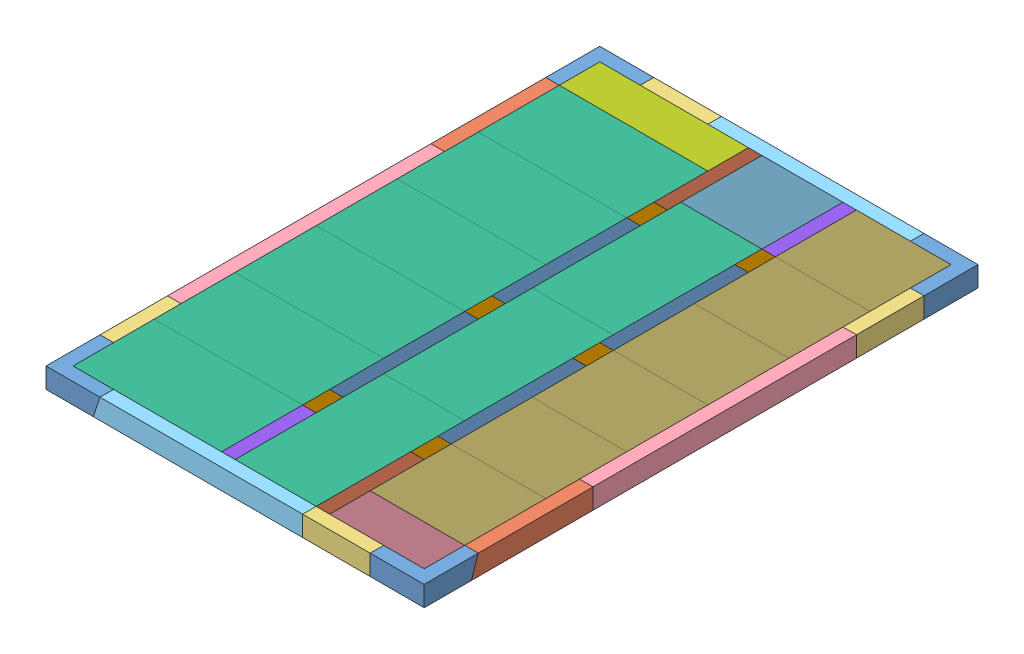
SolidWorks assembly test, configuration 默认. Lengths in mm.
Overall size (2800 228 4100).
46 component instances, 14 part files, 0 mates.
Components (placement in the parent):
- 10x15Z40A+40-5: 10x15Z40A+40 [默认] at (80031.9977 2785.0001 -12041.9998) x (0 0 1) z (0 1 0) size (400 400 150)
- 10x15J85RB-1: 10x15J85RB [默认] at (80031.9977 2785.0001 -10791.9998) x (-1 0 0) z (0 0 -1) size (100 150 900)
- 10x15J50-1: 10x15J50 [默认] at (80031.9977 2785.0001 -8342) x (-1 0 0) z (0 0 -1) size (100 150 500)
- 10x15J195-3: 10x15J195 [默认] at (80031.9977 2785.0001 -8842) x (-1 0 0) z (0 0 -1) size (100 150 1950)
- 10x15Z40A+40-6: 10x15Z40A+40 [默认] at (82832.0007 2785.0001 -12041.9998) x (-1 0 0) z (0 1 0) size (400 400 150)
- 10x15J150RB-3: 10x15J150RB [默认] at (80931.9992 2785.0001 -12041.9998) x (0 0 -1) z (1 0 0) size (100 150 1550)
- 10x15J50-2: 10x15J50 [默认] at (80431.9992 2785.0001 -12041.9998) x (0 0 -1) z (1 0 0) size (100 150 500)
- 10x15Z40A+40-8: 10x15Z40A+40 [默认] at (82832.0007 2785.0001 -7941.9999) x (0 0 -1) z (0 1 0) size (400 400 150)
- 10x15J85RB-2: 10x15J85RB [默认] at (82832.0007 2785.0001 -9192.0004) size (100 150 900)
- 10x15J50-5: 10x15J50 [默认] at (82832.0007 2785.0001 -11642.0002) size (100 150 500)
- 10x15J195-2: 10x15J195 [默认] at (82832.0007 2785.0001 -11142.0002) size (100 150 1950)
- 10x15Z40A+40-7: 10x15Z40A+40 [默认] at (80031.9977 2785.0001 -7941.9999) x (1 0 0) z (0 1 0) size (400 400 150)
- 10x15J150RB-2: 10x15J150RB [默认] at (81931.9992 2785.0001 -7941.9999) x (0 0 1) z (-1 0 0) size (100 150 1550)
- 10x15J50-6: 10x15J50 [默认] at (82431.9992 2785.0001 -7941.9999) x (0 0 1) z (-1 0 0) size (100 150 500)
- 60D110-1: 60D110 [默认] at (80132.0038 2785.0001 -8041.9998) x (0 0 -1) z (-1 0 0) size (600 65 1100)
- 60D110-2: 60D110 [默认] at (80132.0038 2785.0001 -8642.0002) x (0 0 -1) z (-1 0 0) size (600 65 1100)
- 60D110-3: 60D110 [默认] at (80132.0038 2785.0001 -9241.9996) x (0 0 -1) z (-1 0 0) size (600 65 1100)
- 60D110-4: 60D110 [默认] at (80132.0038 2785.0001 -9842) x (0 0 -1) z (-1 0 0) size (600 65 1100)
- 60D110-5: 60D110 [默认] at (80132.0038 2785.0001 -10442.0004) x (0 0 -1) z (-1 0 0) size (600 65 1100)
- 60D110-6: 60D110 [默认] at (80132.0038 2785.0001 -11041.9998) x (0 0 -1) z (-1 0 0) size (600 65 1100)
- 30D110-1: 30D110 [默认] at (80132.0038 2785.0001 -11642.0002) x (0 0 -1) z (-1 0 0) size (300 65 1100)
- DG60-1: DG60 [默认] at (81232.0023 2785.0001 -8041.9998) x (1 0 0) z (0 1 0) size (130 625.48 70)
- LXC-1: LXC [默认] at (81232.0023 2785.0001 -8842) x (0 0 1) z (0 1 0) size (200 100 228)
- ZG100-1: ZG100 [默认] at (81232.0023 2785.0001 -8842) x (1 0 0) z (0 1 0) size (130 1050.96 70)
- LXC-2: LXC [默认] at (81232.0023 2785.0001 -10041.9998) x (0 0 1) z (0 1 0) size (200 100 228)
- ZG100-2: ZG100 [默认] at (81232.0023 2785.0001 -10041.9998) x (1 0 0) z (0 1 0) size (130 1050.96 70)
- LXC-3: LXC [默认] at (81232.0023 2785.0001 -11241.9996) x (0 0 1) z (0 1 0) size (200 100 228)
- DG70-1: DG70 [默认] at (81332.0007 2785.0001 -11942.0004) x (-1 0 0) z (0 1 0) size (130 725.48 70)
- 60D70-1: 60D70 [默认] at (82732.0023 2785.0001 -11942.0004) x (0 0 1) z (1 0 0) size (600 65 700)
- 60D70-2: 60D70 [默认] at (82732.0023 2785.0001 -11342) x (0 0 1) z (1 0 0) size (600 65 700)
- 60D70-3: 60D70 [默认] at (82732.0023 2785.0001 -10741.9996) x (0 0 1) z (1 0 0) size (600 65 700)
- 60D70-4: 60D70 [默认] at (82732.0023 2785.0001 -10142.0002) x (0 0 1) z (1 0 0) size (600 65 700)
- 60D70-5: 60D70 [默认] at (82732.0023 2785.0001 -9541.9998) x (0 0 1) z (1 0 0) size (600 65 700)
- 60D70-6: 60D70 [默认] at (82732.0023 2785.0001 -8942.0004) x (0 0 1) z (1 0 0) size (600 65 700)
- 30D70-1: 30D70 [默认] at (82732.0023 2785.0001 -8342) x (0 0 1) z (1 0 0) size (300 65 700)
- DG60-2: DG60 [默认] at (82031.9977 2785.0001 -11942.0004) x (-1 0 0) z (0 1 0) size (130 625.48 70)
- LXC-4: LXC [默认] at (82031.9977 2785.0001 -11142.0002) x (0 0 -1) z (0 1 0) size (200 100 228)
- ZG100-3: ZG100 [默认] at (82031.9977 2785.0001 -11142.0002) x (-1 0 0) z (0 1 0) size (130 1050.96 70)
- LXC-5: LXC [默认] at (82031.9977 2785.0001 -9942.0004) x (0 0 -1) z (0 1 0) size (200 100 228)
- ZG100-4: ZG100 [默认] at (82031.9977 2785.0001 -9942.0004) x (-1 0 0) z (0 1 0) size (130 1050.96 70)
- LXC-6: LXC [默认] at (82031.9977 2785.0001 -8741.9996) x (0 0 -1) z (0 1 0) size (200 100 228)
- DG70-2: DG70 [默认] at (81931.9992 2785.0001 -8041.9998) x (1 0 0) z (0 1 0) size (130 725.48 70)
- 60D110-7: 60D110 [默认] at (81931.9992 2785.0001 -8041.9998) x (-1 0 0) z (0 0 1) size (600 65 1100)
- 60D110-8: 60D110 [默认] at (81931.9992 2785.0001 -9142.0002) x (-1 0 0) z (0 0 1) size (600 65 1100)
- 60D60-1: 60D60 [默认] at (81931.9992 2785.0001 -11942.0004) x (0 0 1) z (1 0 0) size (600 65 600)
- 60D110-9: 60D110 [默认] at (81931.9992 2785.0001 -10241.9996) x (-1 0 0) z (0 0 1) size (600 65 1100)
